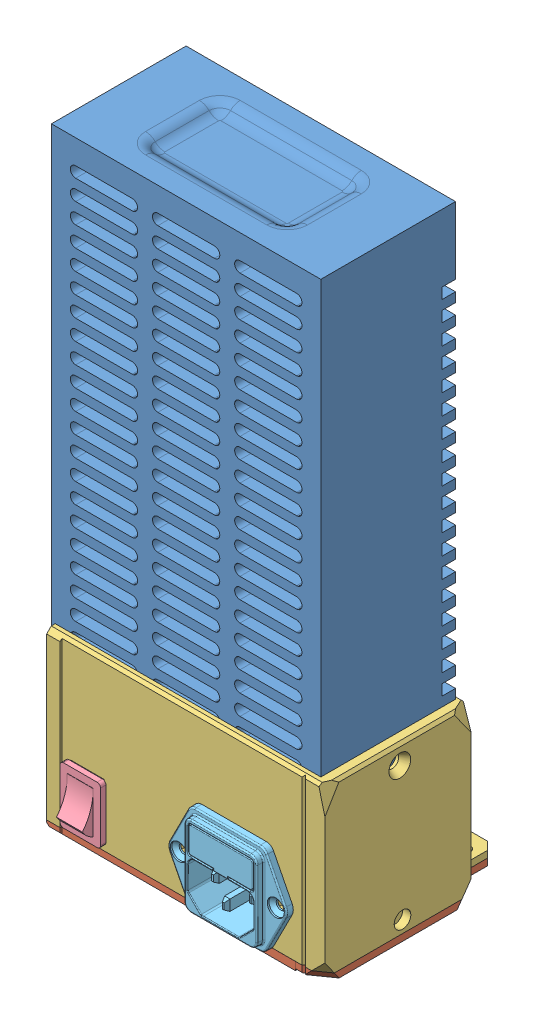
SolidWorks assembly PSU_Assembly, configuration Default. Lengths in mm.
Overall size (135.2 224.5 87.66).
5 component instances, 5 part files, 12 mates.
Components (placement in the parent):
- PSU_Metal-1: PSU_Metal [Default] at (-57.5457 18.634 -7.2936) size (100 195 50)
- PSU-cover-MK3_bottom-1: PSU-cover-MK3_bottom [Default] at (-104.5457 -108.866 -8.6136) size (102.6 13.5 72.5)
- PSU-cover-MK3_top-1: PSU-cover-MK3_top [Default] at (-104.5457 -108.866 -8.6136) size (103 61.5 72.5)
- PSU_switch-1: PSU_switch [Default] at (-83.1901 -109.3664 -9.1136) x (0 1 0) z (0 0 1) size (21.31 15.01 24.84)
- PSU_plug-1: PSU_plug [Default] at (-101.7957 -106.866 -9.8236) size (44 34 28.25)
Mates (geometry in assembly coordinates):
- Coincident1: coincident anti-aligned: plane of PSU-cover-MK3_bottom-1 through (-109.5457 -105.366 -28.6136) normal (0 1 0); plane of PSU-cover-MK3_top-1 through (-109.5457 -105.366 -28.6136) normal (0 -1 0)
- Coincident2: coincident aligned: plane of PSU-cover-MK3_bottom-1 through (-3.5457 -108.866 -9.0736) normal (1 0 0); plane of PSU-cover-MK3_top-1 through (-3.5457 -108.866 -9.0736) normal (1 0 0)
- Coincident3: coincident aligned: plane of PSU-cover-MK3_bottom-1 through (-104.5457 -108.866 45.1764) normal (0 0 1); plane of PSU-cover-MK3_top-1 through (-104.5457 -108.866 45.1764) normal (0 0 1)
- Coincident4: coincident anti-aligned: plane of PSU_Metal-1 through (-7.5457 -78.866 42.7064) normal (1 0 0); plane of PSU-cover-MK3_top-1 through (-7.5457 -60.266 -6.6136) normal (-1 0 0)
- Coincident5: coincident anti-aligned: plane of PSU_Metal-1 through (-57.5457 18.634 42.7064) normal (0 0 1); plane of PSU-cover-MK3_top-1 through (-101.5457 -105.866 42.7064) normal (0 0 -1)
- Coincident6: coincident anti-aligned: plane of PSU_Metal-1 through (-7.5457 -78.866 42.7064) normal (0 -1 0); plane of PSU-cover-MK3_top-1 through (-106.1457 -78.866 -8.6136) normal (0 1 0)
- Coincident7: coincident aligned: plane of PSU-cover-MK3_top-1 through (-85.5457 -102.366 35.3864) normal (-1 0 0); plane of PSU_switch-1 through (-85.5457 -100.9639 47.893) normal (-1 0 0)
- Coincident9: coincident aligned: plane of PSU-cover-MK3_top-1 through (-104.5457 -92.366 -8.6136) normal (0 -1 0); plane of PSU_switch-1 through (-83.1901 -92.366 -9.1136) normal (0 -1 0)
- Coincident10: coincident aligned: plane of PSU-cover-MK3_top-1 through (-106.1457 -107.866 45.8864) normal (0 0 1); plane of PSU_switch-1 through (-91.6417 -92.366 45.8864) normal (0 0 1)
- Coincident11: coincident anti-aligned: plane of PSU-cover-MK3_top-1 through (-104.5457 -89.266 -8.6136) normal (0 -1 0); plane of PSU_plug-1 through (-101.7957 -89.266 -9.8236) normal (0 1 0)
- Coincident12: coincident anti-aligned: plane of PSU-cover-MK3_top-1 through (-37.2957 -108.866 -8.6136) normal (1 0 0); plane of PSU_plug-1 through (-37.2957 -106.866 -9.8236) normal (-1 0 0)
- Coincident13: coincident anti-aligned: plane of PSU-cover-MK3_top-1 through (-104.5457 -108.866 45.1764) normal (0 0 1); plane of PSU_plug-1 through (-55.2957 -89.266 45.1764) normal (0 0 -1)
